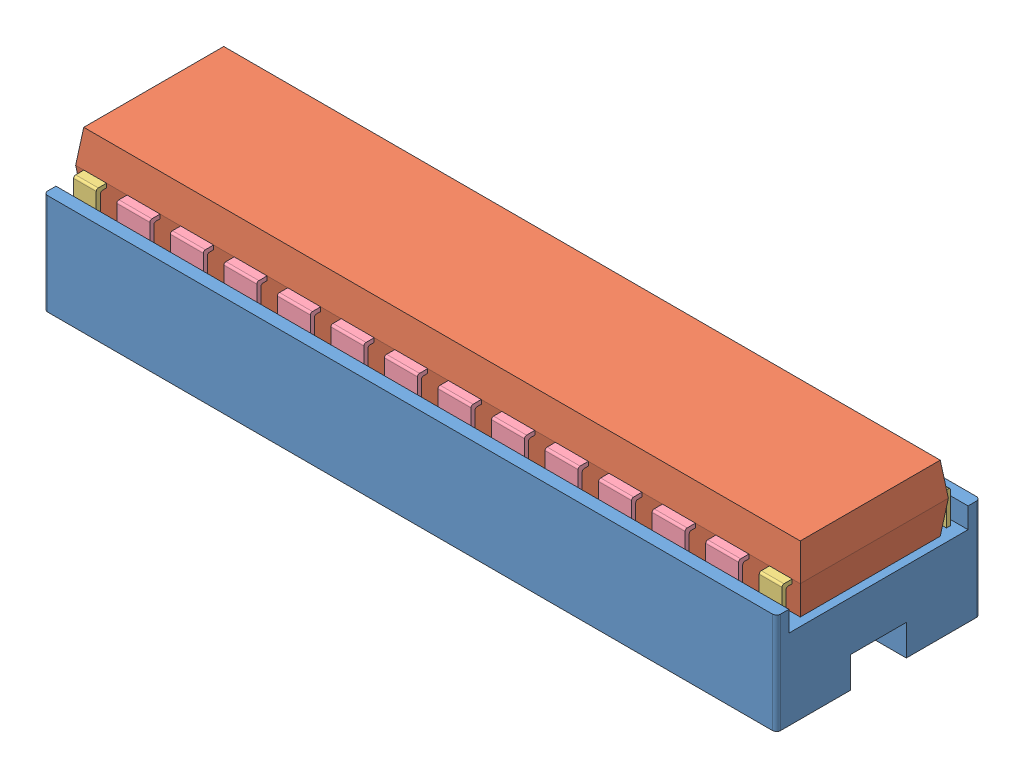
SolidWorks assembly Chip, configuration Défaut. Lengths in mm.
Overall size (35.6 7.1 9.9).
30 component instances, 4 part files, 88 mates.
Components (placement in the parent):
- base chip-1: base chip [Défaut] at (-28.4898 -3.5653 58.5501) size (35.6 4.9 9.9)
- box-1: box [Défaut] at (-28.0898 0.3347 57.0001) size (35.19 3.2 7.19)
- foot (chip)-1: foot (chip) [Défaut] at (-27.8862 -1.0653 57.6966) size (1.1 3 0.5)
- foot (chip)-2: foot (chip) [Défaut] at (5.4138 -1.0653 57.6966) size (1.1 3 0.5)
- foot (big chip)-2: foot (big chip) [Défaut] at (-25.7862 -1.0653 57.6966) size (1.6 3 0.5)
- foot (big chip)-3: foot (big chip) [Défaut] at (-23.1862 -1.0653 57.6966) size (1.6 3 0.5)
- foot (big chip)-4: foot (big chip) [Défaut] at (-20.5862 -1.0653 57.6966) size (1.6 3 0.5)
- foot (big chip)-5: foot (big chip) [Défaut] at (-17.9862 -1.0653 57.6966) size (1.6 3 0.5)
- foot (big chip)-6: foot (big chip) [Défaut] at (-15.3862 -1.0653 57.6966) size (1.6 3 0.5)
- foot (big chip)-7: foot (big chip) [Défaut] at (-12.7862 -1.0653 57.6966) size (1.6 3 0.5)
- foot (big chip)-8: foot (big chip) [Défaut] at (-10.1862 -1.0653 57.6966) size (1.6 3 0.5)
- foot (big chip)-9: foot (big chip) [Défaut] at (-7.5862 -1.0653 57.6966) size (1.6 3 0.5)
- foot (big chip)-10: foot (big chip) [Défaut] at (-4.9862 -1.0653 57.6966) size (1.6 3 0.5)
- foot (big chip)-11: foot (big chip) [Défaut] at (-2.3862 -1.0653 57.6966) size (1.6 3 0.5)
- foot (big chip)-12: foot (big chip) [Défaut] at (0.2138 -1.0653 57.6966) size (1.6 3 0.5)
- foot (big chip)-13: foot (big chip) [Défaut] at (2.8138 -1.0653 57.6966) size (1.6 3 0.5)
- foot (chip)-3: foot (chip) [Défaut] at (6.5138 -1.0653 49.5036) x (-1 0 0) z (0 0 -1) size (1.1 3 0.5)
- foot (big chip)-14: foot (big chip) [Défaut] at (4.4138 -1.0653 49.5036) x (-1 0 0) z (0 0 -1) size (1.6 3 0.5)
- foot (big chip)-15: foot (big chip) [Défaut] at (1.8138 -1.0653 49.5036) x (-1 0 0) z (0 0 -1) size (1.6 3 0.5)
- foot (big chip)-16: foot (big chip) [Défaut] at (-0.7862 -1.0653 49.5036) x (-1 0 0) z (0 0 -1) size (1.6 3 0.5)
- foot (big chip)-17: foot (big chip) [Défaut] at (-3.3862 -1.0653 49.5036) x (-1 0 0) z (0 0 -1) size (1.6 3 0.5)
- foot (big chip)-18: foot (big chip) [Défaut] at (-5.9862 -1.0653 49.5036) x (-1 0 0) z (0 0 -1) size (1.6 3 0.5)
- foot (big chip)-19: foot (big chip) [Défaut] at (-8.5862 -1.0653 49.5036) x (-1 0 0) z (0 0 -1) size (1.6 3 0.5)
- foot (big chip)-20: foot (big chip) [Défaut] at (-11.1862 -1.0653 49.5036) x (-1 0 0) z (0 0 -1) size (1.6 3 0.5)
- foot (big chip)-21: foot (big chip) [Défaut] at (-13.7862 -1.0653 49.5036) x (-1 0 0) z (0 0 -1) size (1.6 3 0.5)
- foot (big chip)-22: foot (big chip) [Défaut] at (-16.3862 -1.0653 49.5036) x (-1 0 0) z (0 0 -1) size (1.6 3 0.5)
- foot (big chip)-23: foot (big chip) [Défaut] at (-18.9862 -1.0653 49.5036) x (-1 0 0) z (0 0 -1) size (1.6 3 0.5)
- foot (big chip)-24: foot (big chip) [Défaut] at (-21.5862 -1.0653 49.5036) x (-1 0 0) z (0 0 -1) size (1.6 3 0.5)
- foot (big chip)-25: foot (big chip) [Défaut] at (-24.1862 -1.0653 49.5036) x (-1 0 0) z (0 0 -1) size (1.6 3 0.5)
- foot (chip)-4: foot (chip) [Défaut] at (-26.7862 -1.0653 49.5036) x (-1 0 0) z (0 0 -1) size (1.1 3 0.5)
Mates (geometry in assembly coordinates):
- Coïncidente1: coincident anti-aligned: plane of base chip-1 through (-28.4898 0.3347 58.5501) normal (0 1 0); plane of box-1 through (-28.0898 0.3347 57.0001) normal (0 -1 0)
- Distance1: distance = 0.95 mm: line of box-1 through (6.7102 0.3347 50.2001) axis (-1 0 0); line of base chip-1 through (-28.4898 0.3347 49.2501) axis (1 0 0)
- Distance2: distance = 0.4 mm: line of box-1 through (-28.0898 0.3347 50.2001) axis (0 0 1); line of base chip-1 through (-28.4898 0.3347 49.2501) axis (0 0 1)
- Coïncidente4: coincident aligned: line of box-1 through (-28.2862 1.9347 57.1966) axis (1 0 0); line of foot (chip)-1 through (-27.8862 1.9347 57.1966) axis (1 0 0)
- Parallèle1: parallel anti-aligned: plane of base chip-1 through (-28.4898 1.3347 57.9501) normal (0 0 -1); plane of foot (chip)-1 through (-27.8862 -1.0653 57.6966) normal (0 0 1)
- Parallèle2: parallel anti-aligned: plane of base chip-1 through (-28.4898 1.3347 57.9501) normal (0 0 -1); plane of foot (big chip)-2 through (-25.7862 -1.0653 57.6966) normal (0 0 1)
- Parallèle3: parallel aligned: plane of base chip-1 through (-28.4898 1.3347 57.9501) normal (0 0 -1); plane of foot (big chip)-3 through (-23.1862 -1.0653 57.4966) normal (0 0 -1)
- Parallèle4: parallel aligned: plane of base chip-1 through (-28.4898 1.3347 57.9501) normal (0 0 -1); plane of foot (big chip)-4 through (-20.5862 -1.0653 57.4966) normal (0 0 -1)
- Parallèle5: parallel aligned: plane of base chip-1 through (-28.4898 1.3347 57.9501) normal (0 0 -1); plane of foot (big chip)-5 through (-17.9862 -1.0653 57.4966) normal (0 0 -1)
- Parallèle6: parallel aligned: plane of base chip-1 through (-28.4898 1.3347 57.9501) normal (0 0 -1); plane of foot (big chip)-6 through (-15.3862 -1.0653 57.4966) normal (0 0 -1)
- Parallèle8: parallel aligned: plane of base chip-1 through (-28.4898 1.3347 57.9501) normal (0 0 -1); plane of foot (big chip)-8 through (-10.1862 -1.0653 57.4966) normal (0 0 -1)
- Parallèle9: parallel aligned: plane of base chip-1 through (-28.4898 1.3347 57.9501) normal (0 0 -1); plane of foot (big chip)-9 through (-7.5862 -1.0653 57.4966) normal (0 0 -1)
- Parallèle10: parallel aligned: plane of base chip-1 through (-28.4898 1.3347 57.9501) normal (0 0 -1); plane of foot (big chip)-10 through (-4.9862 -1.0653 57.4966) normal (0 0 -1)
- Parallèle11: parallel aligned: plane of base chip-1 through (-28.4898 1.3347 57.9501) normal (0 0 -1); plane of foot (big chip)-10 through (-4.9862 -1.0653 57.4966) normal (0 0 -1)
- Parallèle12: parallel aligned: plane of base chip-1 through (-28.4898 1.3347 57.9501) normal (0 0 -1); plane of foot (big chip)-11 through (-2.3862 -1.0653 57.4966) normal (0 0 -1)
- Parallèle13: parallel aligned: plane of base chip-1 through (-28.4898 1.3347 57.9501) normal (0 0 -1); plane of foot (big chip)-13 through (2.8138 -1.0653 57.4966) normal (0 0 -1)
- Coïncidente19: coincident aligned: line of box-1 through (-28.2862 1.9347 57.1966) axis (1 0 0); line of foot (big chip)-2 through (-25.7862 1.9347 57.1966) axis (1 0 0)
- Coïncidente20: coincident aligned: line of box-1 through (-28.2862 1.9347 57.1966) axis (1 0 0); line of foot (big chip)-3 through (-23.1862 1.9347 57.1966) axis (1 0 0)
- Coïncidente21: coincident aligned: line of box-1 through (-28.2862 1.9347 57.1966) axis (1 0 0); line of foot (big chip)-4 through (-20.5862 1.9347 57.1966) axis (1 0 0)
- Coïncidente22: coincident aligned: line of box-1 through (-28.2862 1.9347 57.1966) axis (1 0 0); line of foot (big chip)-5 through (-17.9862 1.9347 57.1966) axis (1 0 0)
- Coïncidente23: coincident aligned: line of box-1 through (-28.2862 1.9347 57.1966) axis (1 0 0); line of foot (big chip)-6 through (-15.3862 1.9347 57.1966) axis (1 0 0)
- Coïncidente24: coincident aligned: line of box-1 through (-28.2862 1.9347 57.1966) axis (1 0 0); line of foot (big chip)-7 through (-12.7862 1.9347 57.1966) axis (1 0 0)
- Coïncidente25: coincident aligned: line of box-1 through (-28.2862 1.9347 57.1966) axis (1 0 0); line of foot (big chip)-8 through (-10.1862 1.9347 57.1966) axis (1 0 0)
- Coïncidente26: coincident aligned: line of box-1 through (-28.2862 1.9347 57.1966) axis (1 0 0); line of foot (big chip)-9 through (-7.5862 1.9347 57.1966) axis (1 0 0)
- Coïncidente27: coincident aligned: line of box-1 through (-28.2862 1.9347 57.1966) axis (1 0 0); line of foot (big chip)-10 through (-4.9862 1.9347 57.1966) axis (1 0 0)
- Coïncidente28: coincident aligned: line of box-1 through (-28.2862 1.9347 57.1966) axis (1 0 0); line of foot (big chip)-11 through (-2.3862 1.9347 57.1966) axis (1 0 0)
- Coïncidente29: coincident aligned: line of box-1 through (-28.2862 1.9347 57.1966) axis (1 0 0); line of foot (big chip)-12 through (0.2138 1.9347 57.1966) axis (1 0 0)
- Coïncidente30: coincident aligned: line of box-1 through (-28.2862 1.9347 57.1966) axis (1 0 0); line of foot (big chip)-13 through (2.8138 1.9347 57.1966) axis (1 0 0)
- Coïncidente31: coincident aligned: line of box-1 through (-28.2862 1.9347 57.1966) axis (1 0 0); line of foot (chip)-2 through (5.4138 1.9347 57.1966) axis (1 0 0)
- Parallèle14: parallel anti-aligned: plane of base chip-1 through (-28.4898 1.3347 57.9501) normal (0 0 -1); plane of foot (big chip)-12 through (0.2138 -1.0653 57.6966) normal (0 0 1)
- Distance3: distance = 0.4 mm: line of foot (chip)-1 through (-27.8862 1.9347 57.1966) axis (0 0 1); point of box-1
- Distance4: distance = 1 mm: line of foot (chip)-1 through (-26.7862 1.9347 57.1966) axis (0 0 1); line of foot (big chip)-2 through (-25.7862 1.9347 57.1966) axis (0 0 1)
- Distance5: distance = 1 mm: line of foot (big chip)-2 through (-24.1862 1.9347 57.1966) axis (0 0 1); line of foot (big chip)-3 through (-23.1862 1.9347 57.1966) axis (0 0 1)
- Distance6: distance = 1 mm: line of foot (big chip)-3 through (-21.5862 1.9347 57.1966) axis (0 0 1); line of foot (big chip)-4 through (-20.5862 1.9347 57.1966) axis (0 0 1)
- Distance7: distance = 1 mm: line of foot (big chip)-5 through (-17.9862 1.9347 57.1966) axis (0 0 1); line of foot (big chip)-4 through (-18.9862 1.9347 57.1966) axis (0 0 1)
- Distance8: distance = 1 mm: line of foot (big chip)-5 through (-16.3862 1.9347 57.1966) axis (0 0 1); line of foot (big chip)-6 through (-15.3862 1.9347 57.1966) axis (0 0 1)
- Distance9: distance = 1 mm: line of foot (big chip)-6 through (-13.7862 1.9347 57.1966) axis (0 0 1); line of foot (big chip)-7 through (-12.7862 1.9347 57.1966) axis (0 0 1)
- Distance10: distance = 1 mm: line of foot (big chip)-7 through (-11.1862 1.9347 57.1966) axis (0 0 1); line of foot (big chip)-8 through (-10.1862 1.9347 57.1966) axis (0 0 1)
- Distance11: distance = 1 mm: line of foot (big chip)-8 through (-8.5862 1.9347 57.1966) axis (0 0 1); line of foot (big chip)-9 through (-7.5862 1.9347 57.1966) axis (0 0 1)
- Distance12: distance = 1 mm: line of foot (big chip)-9 through (-5.9862 1.9347 57.1966) axis (0 0 1); line of foot (big chip)-10 through (-4.9862 1.9347 57.1966) axis (0 0 1)
- Distance13: distance = 1 mm: line of foot (big chip)-10 through (-3.3862 1.9347 57.1966) axis (0 0 1); line of foot (big chip)-11 through (-2.3862 1.9347 57.1966) axis (0 0 1)
- Distance14: distance = 1 mm: line of foot (big chip)-11 through (-0.7862 1.9347 57.1966) axis (0 0 1); line of foot (big chip)-12 through (0.2138 1.9347 57.1966) axis (0 0 1)
- Distance15: distance = 1 mm: line of foot (big chip)-12 through (1.8138 1.9347 57.1966) axis (0 0 1); line of foot (big chip)-13 through (2.8138 1.9347 57.1966) axis (0 0 1)
- Distance16: distance = 1 mm: line of foot (big chip)-13 through (4.4138 1.9347 57.1966) axis (0 0 1); line of foot (chip)-2 through (5.4138 1.9347 57.1966) axis (0 0 1)
- Parallèle15: parallel aligned: plane of base chip-1 through (-28.4898 0.3347 48.6501) normal (0 0 -1); plane of foot (chip)-3 through (6.5138 -1.0653 49.5036) normal (0 0 -1)
- Parallèle16: parallel aligned: plane of base chip-1 through (-28.4898 0.3347 48.6501) normal (0 0 -1); plane of foot (big chip)-14 through (4.4138 -1.0653 49.5036) normal (0 0 -1)
- Parallèle17: parallel aligned: plane of base chip-1 through (-28.4898 0.3347 48.6501) normal (0 0 -1); plane of foot (big chip)-15 through (1.8138 -1.0653 49.5036) normal (0 0 -1)
- Parallèle18: parallel aligned: plane of base chip-1 through (-28.4898 0.3347 48.6501) normal (0 0 -1); plane of foot (big chip)-16 through (-0.7862 -1.0653 49.5036) normal (0 0 -1)
- Parallèle19: parallel aligned: plane of base chip-1 through (-28.4898 0.3347 48.6501) normal (0 0 -1); plane of foot (big chip)-17 through (-3.3862 -1.0653 49.5036) normal (0 0 -1)
- Parallèle20: parallel aligned: plane of base chip-1 through (-28.4898 0.3347 48.6501) normal (0 0 -1); plane of foot (big chip)-18 through (-5.9862 -1.0653 49.5036) normal (0 0 -1)
- Parallèle21: parallel aligned: plane of base chip-1 through (-28.4898 0.3347 48.6501) normal (0 0 -1); plane of foot (big chip)-19 through (-8.5862 -1.0653 49.5036) normal (0 0 -1)
- Parallèle22: parallel aligned: plane of base chip-1 through (-28.4898 0.3347 48.6501) normal (0 0 -1); plane of foot (big chip)-20 through (-11.1862 -1.0653 49.5036) normal (0 0 -1)
- Parallèle23: parallel aligned: plane of base chip-1 through (-28.4898 0.3347 48.6501) normal (0 0 -1); plane of foot (big chip)-21 through (-13.7862 -1.0653 49.5036) normal (0 0 -1)
- Parallèle24: parallel aligned: plane of base chip-1 through (-28.4898 0.3347 48.6501) normal (0 0 -1); plane of foot (big chip)-22 through (-16.3862 -1.0653 49.5036) normal (0 0 -1)
- Parallèle25: parallel aligned: plane of base chip-1 through (-28.4898 0.3347 48.6501) normal (0 0 -1); plane of foot (big chip)-23 through (-18.9862 -1.0653 49.5036) normal (0 0 -1)
- Parallèle26: parallel aligned: plane of base chip-1 through (-28.4898 0.3347 48.6501) normal (0 0 -1); plane of foot (big chip)-24 through (-21.5862 -1.0653 49.5036) normal (0 0 -1)
- Parallèle27: parallel aligned: plane of base chip-1 through (-28.4898 0.3347 48.6501) normal (0 0 -1); plane of foot (big chip)-25 through (-24.1862 -1.0653 49.5036) normal (0 0 -1)
- Parallèle28: parallel aligned: plane of base chip-1 through (-28.4898 0.3347 48.6501) normal (0 0 -1); plane of foot (chip)-4 through (-26.7862 -1.0653 49.5036) normal (0 0 -1)
- Coïncidente60: coincident aligned: line of box-1 through (6.9067 1.9347 50.0036) axis (-1 0 0); line of foot (chip)-4 through (-26.7862 1.9347 50.0036) axis (-1 0 0)
- Parallèle29: parallel anti-aligned: plane of base chip-1 through (-28.4898 1.3347 57.9501) normal (0 0 -1); plane of foot (chip)-2 through (5.4138 -1.0653 57.6966) normal (0 0 1)
- Parallèle30: parallel anti-aligned: plane of base chip-1 through (-28.4898 1.3347 57.9501) normal (0 0 -1); plane of foot (big chip)-7 through (-12.7862 -1.0653 57.6966) normal (0 0 1)
- Coïncidente72: coincident aligned: line of box-1 through (6.9067 1.9347 50.0036) axis (-1 0 0); line of foot (big chip)-25 through (-24.1862 1.9347 50.0036) axis (-1 0 0)
- Coïncidente73: coincident aligned: line of box-1 through (6.9067 1.9347 50.0036) axis (-1 0 0); line of foot (big chip)-24 through (-21.5862 1.9347 50.0036) axis (-1 0 0)
- Coïncidente74: coincident aligned: line of box-1 through (6.9067 1.9347 50.0036) axis (-1 0 0); line of foot (big chip)-23 through (-18.9862 1.9347 50.0036) axis (-1 0 0)
- Coïncidente75: coincident aligned: line of box-1 through (6.9067 1.9347 50.0036) axis (-1 0 0); line of foot (big chip)-22 through (-16.3862 1.9347 50.0036) axis (-1 0 0)
- Coïncidente76: coincident aligned: line of box-1 through (6.9067 1.9347 50.0036) axis (-1 0 0); line of foot (big chip)-21 through (-13.7862 1.9347 50.0036) axis (-1 0 0)
- Coïncidente77: coincident aligned: line of box-1 through (6.9067 1.9347 50.0036) axis (-1 0 0); line of foot (big chip)-20 through (-11.1862 1.9347 50.0036) axis (-1 0 0)
- Coïncidente78: coincident aligned: line of box-1 through (6.9067 1.9347 50.0036) axis (-1 0 0); line of foot (big chip)-19 through (-8.5862 1.9347 50.0036) axis (-1 0 0)
- Coïncidente79: coincident aligned: line of box-1 through (6.9067 1.9347 50.0036) axis (-1 0 0); line of foot (big chip)-18 through (-5.9862 1.9347 50.0036) axis (-1 0 0)
- Coïncidente80: coincident aligned: line of box-1 through (6.9067 1.9347 50.0036) axis (-1 0 0); line of foot (big chip)-17 through (-3.3862 1.9347 50.0036) axis (-1 0 0)
- Coïncidente81: coincident aligned: line of box-1 through (6.9067 1.9347 50.0036) axis (-1 0 0); line of foot (big chip)-16 through (-0.7862 1.9347 50.0036) axis (-1 0 0)
- Coïncidente82: coincident aligned: line of box-1 through (6.9067 1.9347 50.0036) axis (-1 0 0); line of foot (big chip)-15 through (1.8138 1.9347 50.0036) axis (-1 0 0)
- Coïncidente83: coincident aligned: line of box-1 through (6.9067 1.9347 50.0036) axis (-1 0 0); line of foot (big chip)-14 through (4.4138 1.9347 50.0036) axis (-1 0 0)
- Coïncidente84: coincident aligned: line of box-1 through (6.9067 1.9347 50.0036) axis (-1 0 0); line of foot (chip)-3 through (6.5138 1.9347 50.0036) axis (-1 0 0)
- Distance18: distance = 1 mm: line of foot (chip)-3 through (5.4138 1.9347 50.0036) axis (0 0 -1); line of foot (big chip)-14 through (4.4138 1.9347 50.0036) axis (0 0 -1)
- Distance19: distance = 1 mm: line of foot (big chip)-14 through (2.8138 1.9347 50.0036) axis (0 0 -1); line of foot (big chip)-15 through (1.8138 1.9347 50.0036) axis (0 0 -1)
- Distance20: distance = 1 mm: line of foot (big chip)-15 through (0.2138 1.9347 50.0036) axis (0 0 -1); line of foot (big chip)-16 through (-0.7862 1.9347 50.0036) axis (0 0 -1)
- Distance21: distance = 1 mm: line of foot (big chip)-16 through (-2.3862 1.9347 50.0036) axis (0 0 -1); line of foot (big chip)-17 through (-3.3862 1.9347 50.0036) axis (0 0 -1)
- Distance22: distance = 1 mm: line of foot (big chip)-17 through (-4.9862 1.9347 50.0036) axis (0 0 -1); line of foot (big chip)-18 through (-5.9862 1.9347 50.0036) axis (0 0 -1)
- Distance23: distance = 1 mm: line of foot (big chip)-19 through (-8.5862 1.9347 50.0036) axis (0 0 -1); line of foot (big chip)-18 through (-7.5862 1.9347 50.0036) axis (0 0 -1)
- Distance24: distance = 1 mm: line of foot (big chip)-20 through (-11.1862 1.9347 50.0036) axis (0 0 -1); line of foot (big chip)-19 through (-10.1862 1.9347 50.0036) axis (0 0 -1)
- Distance25: distance = 1 mm: line of foot (big chip)-21 through (-13.7862 1.9347 50.0036) axis (0 0 -1); line of foot (big chip)-20 through (-12.7862 1.9347 50.0036) axis (0 0 -1)
- Distance26: distance = 1 mm: line of foot (big chip)-21 through (-15.3862 1.9347 50.0036) axis (0 0 -1); line of foot (big chip)-22 through (-16.3862 1.9347 50.0036) axis (0 0 -1)
- Distance27: distance = 1 mm: line of foot (big chip)-22 through (-17.9862 1.9347 50.0036) axis (0 0 -1); line of foot (big chip)-23 through (-18.9862 1.9347 50.0036) axis (0 0 -1)
- Distance28: distance = 1 mm: line of foot (big chip)-23 through (-20.5862 1.9347 50.0036) axis (0 0 -1); line of foot (big chip)-24 through (-21.5862 1.9347 50.0036) axis (0 0 -1)
- Distance29: distance = 1 mm: line of foot (big chip)-24 through (-23.1862 1.9347 50.0036) axis (0 0 -1); line of foot (big chip)-25 through (-24.1862 1.9347 50.0036) axis (0 0 -1)
- Distance30: distance = 1 mm: line of foot (big chip)-25 through (-25.7862 1.9347 50.0036) axis (0 0 -1); line of foot (chip)-4 through (-26.7862 1.9347 50.0036) axis (0 0 -1)
- Distance31: distance = 0.4 mm: line of foot (chip)-4 through (-27.8862 1.9347 50.0036) axis (0 0 -1); point of box-1
